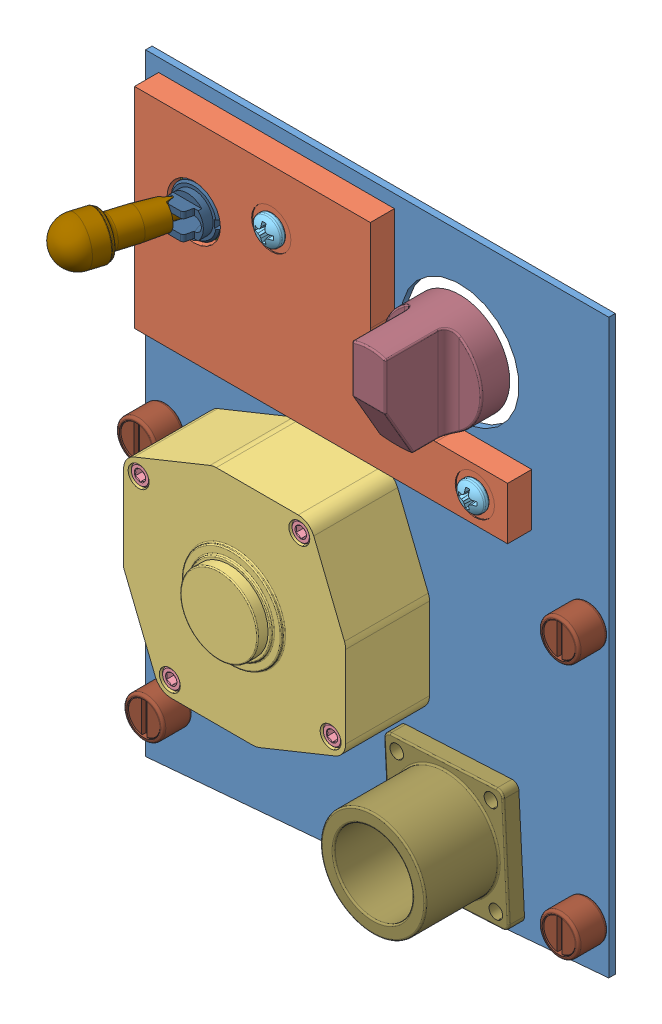
SolidWorks assembly OXY Panel Ref, configuration Default. Lengths in mm.
Overall size (112.27 148.34 40.02).
31 component instances, 14 part files, 0 mates.
Components (placement in the parent):
- OXY Mount Plate-1: OXY Mount Plate [Default] at origin size (112.27 148.34 1.59)
- OXY Light Plate-1: OXY Light Plate [Default] at origin size (90.42 50.8 5.84)
- OXY Misc Component A-1: OXY Misc Component A [Default] at origin size (53.85 53.85 24.13)
  - OXY Misc Component A Case-1: OXY Misc Component A Case [Default] at origin size (53.85 53.85 24.13)
  - No. 4 Socket Head Machine Screw Ref v1-1: No. 4 Socket Head Machine Screw Ref v1 [Default] at (18.6445 -70.0322 18.7325) size (4.65 4.65 4.57)
  - No. 4 Socket Head Machine Screw Ref v1-2: No. 4 Socket Head Machine Screw Ref v1 [Default] at (57.6028 -62.4595 18.7325) size (4.65 4.65 4.57)
  - No. 4 Socket Head Machine Screw Ref v1-3: No. 4 Socket Head Machine Screw Ref v1 [Default] at (65.1755 -101.4178 18.7325) size (4.65 4.65 4.57)
  - No. 4 Socket Head Machine Screw Ref v1-4: No. 4 Socket Head Machine Screw Ref v1 [Default] at (26.2172 -108.9905 18.7325) size (4.65 4.65 4.57)
- No. 6 Pan Head Phillips Machine Screw Ref v2-1: No. 6 Pan Head Phillips Machine Screw Ref v2 [Default] at (36.322 -16.51 4.0005) size (6.9 6.86 4.05)
- No. 6 Pan Head Phillips Machine Screw Ref v2-2: No. 6 Pan Head Phillips Machine Screw Ref v2 [Default] at (85.6615 -47.625 4.0005) size (6.9 6.86 4.05)
- MS25081-4 v1-1: MS25081-4 v1 [Default] at (17.526 -22.352 -1.016) x (0 -1 0) z (0 0 1) size (18.26 19.09 2.29)
- MS25082-8 v2-1: MS25082-8 v2 [Default] at (17.526 -22.352 -2.0066) size (15.08 16.48 1.98)
- MS35333-126 v1-1: MS35333-126 v1 [Default] at (17.526 -22.352 1.8161) size (15.24 15.24 0.71)
- MS25082-8 v2-2: MS25082-8 v2 [Default] at (17.526 -22.352 3.0353) size (15.08 16.48 1.98)
- MS Toggle Switch Locking D Ref v4-1: MS Toggle Switch Locking D Ref v4 [Default] at origin size (21.75 14.29 40.02)
  - Toggle Lever Locking Round Ref-1: Toggle Lever Locking Round Ref [Default] at (19.3083 -22.352 -4.2421) x (0 1 0) z (-0.292372 0 0.956305) size (10.67 10.67 36.48)
  - Toggle Threads Locking Ref-1: Toggle Threads Locking Ref [Default] at (17.526 -22.352 -4.5085) x (0 1 0) z (0 0 1) size (14.29 14.29 17.78)
- D5 DZUS Stud Ref v1-1: D5 DZUS Stud Ref v1 [Default] at (4.8895 -76.2 1.5875) size (9.65 9.65 8.83)
- D5 DZUS Stud Ref v1-2: D5 DZUS Stud Ref v1 [Default] at (6.731 -133.35 1.5875) size (9.65 9.65 8.83)
- D5 DZUS Stud Ref v1-3: D5 DZUS Stud Ref v1 [Default] at (107.3785 -66.675 1.5875) size (9.65 9.65 8.83)
- D5 DZUS Stud Ref v1-4: D5 DZUS Stud Ref v1 [Default] at (107.3785 -128.5875 1.5875) size (9.65 9.65 8.83)
- OXY Misc Component B-1: OXY Misc Component B [Default] at origin size (30.27 30.27 21.59)
- No. 4 Pan Head Phillips Machine Screw Ref v1-1: No. 4 Pan Head Phillips Machine Screw Ref v1 [Default] at origin size (5.59 5.56 3.62)
  - 91249A101-1: 91249A101 [Default] at (64.6955 -113.0089 2.2225) size (5.59 5.56 3.62)
- No. 4 Pan Head Phillips Machine Screw Ref v1_2-1: No. 4 Pan Head Phillips Machine Screw Ref v1_2 [Default] at origin size (5.59 5.56 3.62)
  - 91249A101-1: 91249A101 [Default] at (88.7205 -134.6411 2.2225) size (5.59 5.56 3.62)
- No. 4 Pan Head Phillips Machine Screw Ref v1_3-1: No. 4 Pan Head Phillips Machine Screw Ref v1_3 [Default] at origin size (5.59 5.56 3.62)
  - 91249A101-1: 91249A101 [Default] at (87.5241 -111.8125 2.2225) size (5.59 5.56 3.62)
- No. 4 Pan Head Phillips Machine Screw Ref v1_4-1: No. 4 Pan Head Phillips Machine Screw Ref v1_4 [Default] at origin size (5.59 5.56 3.62)
  - 91249A101-1: 91249A101 [Default] at (65.8919 -135.8375 2.2225) size (5.59 5.56 3.62)
- OXY FLOW Knob Ref v2-1: OXY FLOW Knob Ref v2 [Default] at (76.2 -25.4 1.5875) size (24.14 24.33 22.22)
